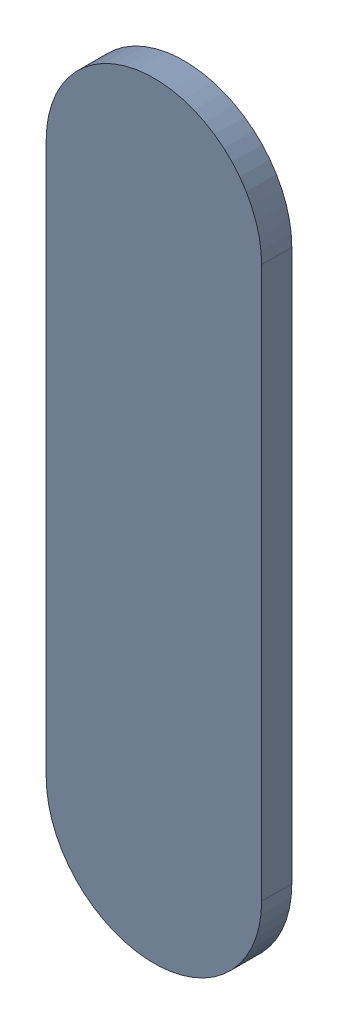
SolidWorks assembly Track (26.95mm,39.35mm)(26.95mm,40mm) on Top Layer, configuration Predeterminado. Lengths in mm.
Overall size (0.25 0.9 0.04).
2 component instances, 1 part files, 0 mates.
Components (placement in the parent):
- Track (26.95mm,39.35mm)(26.95mm,40mm) on Top Layer-1-1: Track (26.95mm,39.35mm)(26.95mm,40mm) on Top Layer-1 [Predeterminado] at (-68.317 -44.187 -0.0457) size (0.25 0.9 0.04)
  - Track (26.95mm,39.35mm)(26.95mm,40mm) on Top Layer-Part-1-1: Track (26.95mm,39.35mm)(26.95mm,40mm) on Top Layer-Part-1 [Predeterminado] at origin size (0.25 0.9 0.04)
